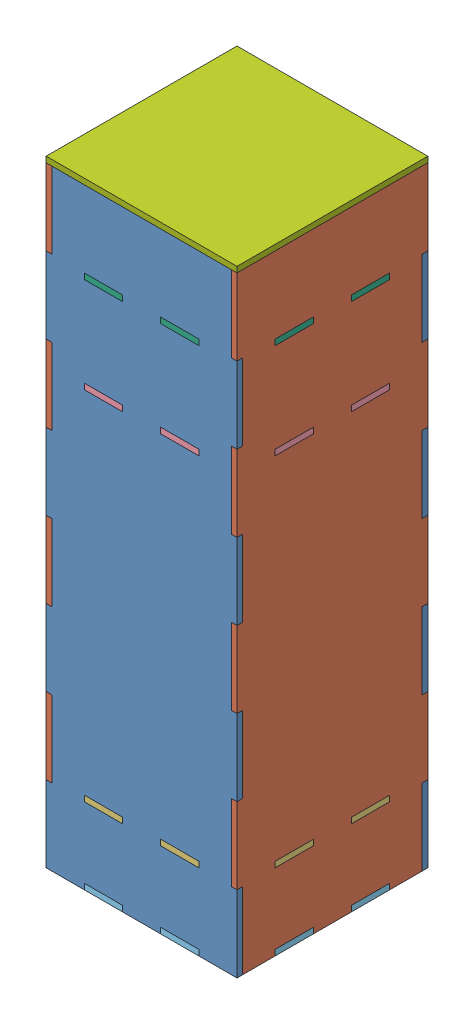
SolidWorks assembly 装配体3, configuration 默认. Lengths in mm.
Overall size (100.02 323 100).
9 component instances, 7 part files, 24 mates.
Components (placement in the parent):
- 天气盒子1-1-1: 天气盒子1-1 [默认] at (-86.1713 -104.4503 318.5) size (100 320 3)
- 天气盒子1-2-1: 天气盒子1-2 [默认] at (-36.1713 111.2374 271.5) x (0 0 -1) z (-1 0 0) size (100 320 3)
- 天气盒子1-1-2: 天气盒子1-1 [默认] at (-86.1713 -104.4503 221.5) size (100 320 3)
- 天气盒子1-2-2: 天气盒子1-2 [默认] at (-133.1713 111.2374 271.5) x (0 0 -1) z (-1 0 0) size (100 320 3)
- 天气盒子2-1-1: 天气盒子2-1 [默认] at (-86.1957 -115.1666 271.5106) x (0 0 -1) z (0 -1 0) size (100 100 3)
- 天气盒子2-2-1: 天气盒子2-2 [默认] at (-86.1606 68.8334 271.5244) x (1 0 0) z (0 1 0) size (100 100 3)
- 天气盒子3-1-1: 天气盒子3-1 [默认] at (-86.1713 -155.1666 271.5) x (1 0 0) z (0 -1 0) size (100 100 3)
- 天气盒子3-2-2: 天气盒子3-2 [默认] at (-86.1713 118.8334 271.5) x (1 0 0) z (0 1 0) size (100 100 3)
- 天气盒子4-1-1: 天气盒子4-1 [默认] at (-87.6302 164.8334 268.9801) x (1 0 0) z (0 -1 0) size (100 100 8)
Mates (geometry in assembly coordinates):
- 重合1: coincident anti-aligned: plane of 天气盒子1-1-1 through (-86.1713 -104.4503 318.5) normal (0 0 -1); plane of 天气盒子1-2-1 through (-39.1713 121.8334 318.5) normal (0 0 1)
- 重合2: coincident anti-aligned: plane of 天气盒子1-1-1 through (-39.1713 41.8334 321.5) normal (1 0 0); plane of 天气盒子1-2-1 through (-39.1713 111.2374 271.5) normal (-1 0 0)
- 重合5: coincident anti-aligned: plane of 天气盒子1-1-1 through (-36.1713 -118.1666 321.5) normal (0 1 0); plane of 天气盒子1-2-1 through (-39.1713 -118.1666 321.5) normal (0 -1 0)
- 重合6: coincident anti-aligned: plane of 天气盒子1-2-1 through (-39.1713 -118.1666 221.5) normal (0 -1 0); plane of 天气盒子1-1-2 through (-36.1713 -118.1666 224.5) normal (0 1 0)
- 重合7: coincident anti-aligned: plane of 天气盒子1-2-1 through (-39.1713 -118.1666 224.5) normal (0 0 -1); plane of 天气盒子1-1-2 through (-86.1713 -104.4503 224.5) normal (0 0 1)
- 重合8: coincident anti-aligned: plane of 天气盒子1-2-1 through (-39.1713 111.2374 271.5) normal (-1 0 0); plane of 天气盒子1-1-2 through (-39.1713 -118.1666 224.5) normal (1 0 0)
- 重合9: coincident anti-aligned: plane of 天气盒子1-1-1 through (-136.1713 -118.1666 321.5) normal (0 1 0); plane of 天气盒子1-2-2 through (-136.1713 -118.1666 321.5) normal (0 -1 0)
- 重合10: coincident anti-aligned: plane of 天气盒子1-1-1 through (-86.1713 -104.4503 318.5) normal (0 0 -1); plane of 天气盒子1-2-2 through (-136.1713 -118.1666 318.5) normal (0 0 1)
- 重合12: coincident anti-aligned: plane of 天气盒子1-1-1 through (-133.1713 -118.1666 321.5) normal (-1 0 0); plane of 天气盒子1-2-2 through (-133.1713 111.2374 271.5) normal (1 0 0)
- 重合13: coincident aligned: plane of 天气盒子1-2-2 through (-136.1713 111.2374 271.5) normal (-1 0 0); plane of 天气盒子2-1-1 through (-136.1713 -118.1666 281.5) normal (-1 0 0)
- 重合14: coincident aligned: plane of 天气盒子1-1-1 through (-86.1713 -104.4503 321.5) normal (0 0 1); plane of 天气盒子2-1-1 through (-96.1713 -118.1666 321.5) normal (0 0 1)
- 重合15: coincident anti-aligned: plane of 天气盒子1-2-2 through (-136.1713 -118.1666 241.5) normal (0 1 0); plane of 天气盒子2-1-1 through (-133.1713 -118.1666 318.5) normal (0 -1 0)
- 重合16: coincident aligned: plane of 天气盒子1-2-1 through (-36.1713 111.2374 271.5) normal (1 0 0); plane of 天气盒子2-2-1 through (-36.1713 71.8334 271.5244) normal (1 0 0)
- 重合17: coincident aligned: plane of 天气盒子1-1-2 through (-86.1713 -104.4503 221.5) normal (0 0 -1); plane of 天气盒子2-2-1 through (-86.1606 71.8334 221.5) normal (0 0 -1)
- 重合18: coincident: line of 天气盒子1-1-2 through (-116.1713 68.8334 221.5) axis (1 0 0); plane of 天气盒子2-2-1 through (-86.1606 68.8334 271.5244) normal (0 -1 0)
- 重合19: coincident anti-aligned: plane of 天气盒子1-2-2 through (-136.1713 -155.1666 261.5) normal (0 -1 0); plane of 天气盒子3-1-1 through (-86.1713 -155.1666 271.5) normal (0 1 0)
- 重合20: coincident aligned: plane of 天气盒子1-2-1 through (-36.1713 111.2374 271.5) normal (1 0 0); plane of 天气盒子3-1-1 through (-36.1713 -158.1666 261.5) normal (1 0 0)
- 重合21: coincident aligned: plane of 天气盒子1-1-2 through (-86.1713 -104.4503 221.5) normal (0 0 -1); plane of 天气盒子3-1-1 through (-96.1713 -158.1666 221.5) normal (0 0 -1)
- 重合22: coincident: plane of 天气盒子1-1-2 through (-86.1713 -104.4503 221.5) normal (0 0 -1); plane of 天气盒子3-2-2 through (-96.1713 121.8334 221.5) normal (0 0 -1)
- 重合23: coincident: plane of 天气盒子1-2-1 through (-36.1713 111.2374 271.5) normal (1 0 0); plane of 天气盒子3-2-2 through (-36.1713 121.8334 261.5) normal (1 0 0)
- 重合24: coincident anti-aligned: plane of 天气盒子1-1-2 through (-56.1713 121.8334 224.5) normal (0 -1 0); plane of 天气盒子3-2-2 through (-86.1713 121.8334 271.5) normal (0 1 0)
- 重合25: coincident: plane of 天气盒子1-2-1 through (-39.1713 111.2374 271.5) normal (-1 0 0); plane of 天气盒子4-1-1 through (-39.1713 161.8334 268.9801) normal (1 0 0)
- 重合26: coincident: plane of 天气盒子1-2-1 through (-39.1713 161.8334 321.5) normal (0 1 0); plane of 天气盒子4-1-1 through (-87.6302 161.8334 268.9801) normal (0 -1 0)
- 重合27: coincident anti-aligned: plane of 天气盒子1-1-1 through (-86.1713 -104.4503 318.5) normal (0 0 -1); plane of 天气盒子4-1-1 through (-87.6302 161.8334 318.5) normal (0 0 1)
